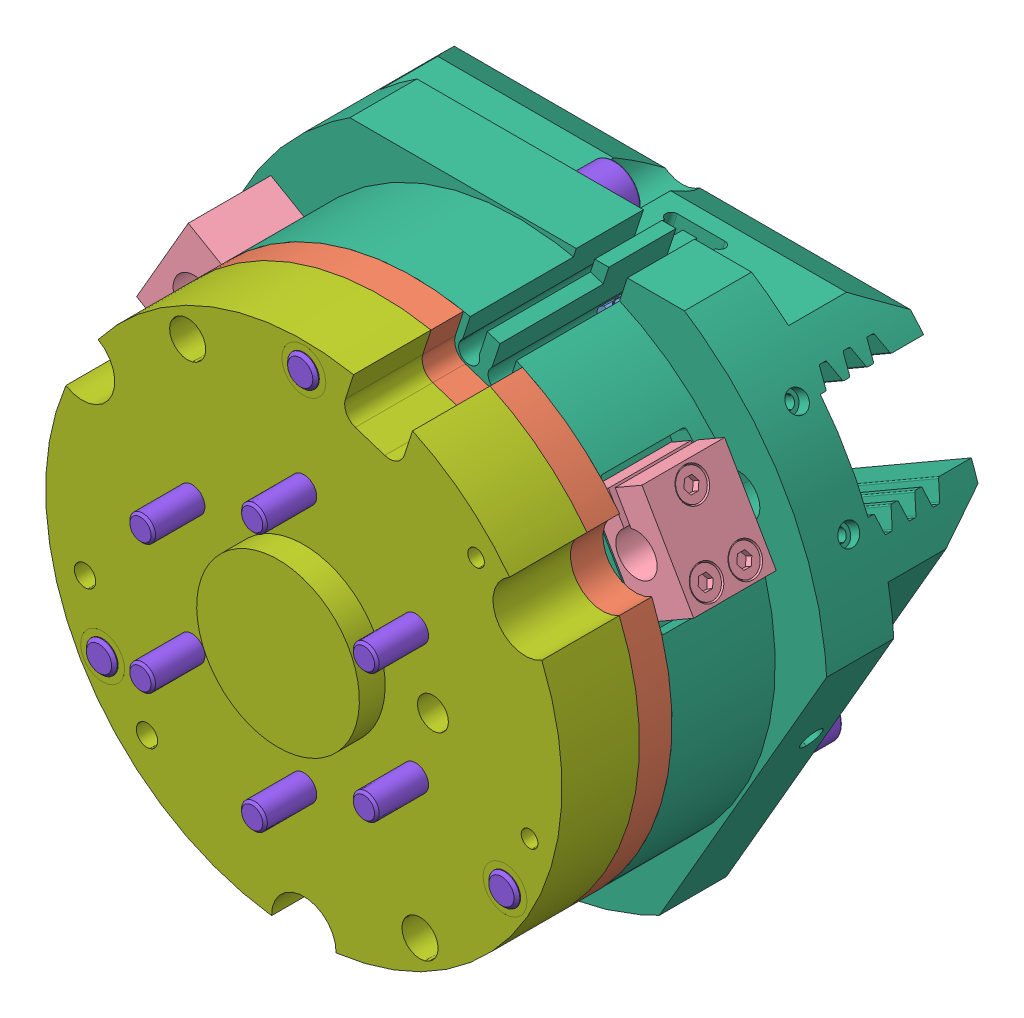
SolidWorks assembly pinza, configuration Default. Lengths in mm.
Overall size (155.63 159.06 83.8).
20 component instances, 9 part files, 17 mates.
Components (placement in the parent):
- SCHUNK_0303312_PZN_plus_100_1__00000-1: SCHUNK_0303312_PZN_plus_100_1__00000 [Default] at (-15.6229 -1.3194 144.3) x (0 -1 0) z (0 0 -1) size (159.06 155.63 58.8)
  - SCHUNK_0303312_PZN_plus_100_1__00000_3-1: SCHUNK_0303312_PZN_plus_100_1__00000_3 [Default] at (-39.3115 -15.8193 29.8) x (0.374607 -0.927184 0) z (0 0 -1) size (3.8 2.96 5)
  - SCHUNK_0303312_PZN_plus_100_1__00000_9-1: SCHUNK_0303312_PZN_plus_100_1__00000_9 [Default] at (0 0 6.3) x (0.866025 -0.5 0) z (0.5 0.866025 0) size (100 6.3 99.61)
  - SCHUNK_0303312_PZN_plus_100_1__00000_11-1: SCHUNK_0303312_PZN_plus_100_1__00000_11 [Default] at (-0.8084 39.8998 57.6) x (0.866025 -0.5 0) z (0 0 1) size (24 9 0.3)
  - SCHUNK_0303312_PZN_plus_100_1__00000_13-1: SCHUNK_0303312_PZN_plus_100_1__00000_13 [Default] at (44.5 0 6.55) x (1 0 0) z (0 -1 0) size (12 16 20)
  - SCHUNK_0303312_PZN_plus_100_1__00000_13-2: SCHUNK_0303312_PZN_plus_100_1__00000_13 [Default] at (-22.25 -38.5381 6.55) x (-0.5 -0.866025 0) z (-0.866025 0.5 0) size (12 16 20)
  - SCHUNK_0303312_PZN_plus_100_1__00000_13-3: SCHUNK_0303312_PZN_plus_100_1__00000_13 [Default] at (-22.25 38.5381 6.55) x (-0.5 0.866025 0) z (0.866025 0.5 0) size (12 16 20)
  - SCHUNK_0303312_PZN_plus_100_1__00000_17-1: SCHUNK_0303312_PZN_plus_100_1__00000_17 [Default] at (0 0 57.3) x (0.5 0.866025 0) z (0.866025 -0.5 0) size (41 1.5 41)
  - SCHUNK_0303312_PZN_plus_100_1__00000_19-1: SCHUNK_0303312_PZN_plus_100_1__00000_19 [Default] at (0 0 6.3) x (-0.866025 0.5 0) z (0.5 0.866025 0) size (119.87 52 110.5)
- IRB4600_20kg-250_LINK6_CAD_rev04.step-1: IRB4600_20kg-250_LINK6_CAD_rev04.step [Default] at (-1780.6229 -1.3194 1649.3) x (0 0 -1) z (1 0 0) size (34 63 63) (hidden)
- flangia-1: flangia [Default] at (-15.6229 -1.3194 144.3) x (0.5 -0.866025 0) z (0 0 1) size (100 99.61 20)
- socket head cap screw_iso-1: socket head cap screw_iso [ISO 4762 M6 x 55 - 24N] at (23.3477 -23.8184 99) x (0 0 1) z (-1 0 0) size (61 10 10)
- socket head cap screw_iso-2: socket head cap screw_iso [ISO 4762 M6 x 55 - 24N] at (-54.5929 -23.8194 99) x (0 0 1) z (0.5 0.866025 0) size (61 10 10)
- socket head cap screw_iso-3: socket head cap screw_iso [ISO 4762 M6 x 55 - 24N] at (-15.6235 43.6796 99) x (0 0 1) z (0.5 -0.866025 0) size (61 10 10)
- socket head cap screw_iso-4: socket head cap screw_iso [ISO 4762 M5 x 20 - 20N] at (-37.2735 -13.8194 144.3) x (0 0 1) z (-1 0 0) size (25 8.5 8.5)
- socket head cap screw_iso-5: socket head cap screw_iso [ISO 4762 M5 x 20 - 20N] at (-15.6229 -26.3194 144.3) x (0 0 1) z (-0.5 -0.866025 0) size (25 8.5 8.5)
- socket head cap screw_iso-6: socket head cap screw_iso [ISO 4762 M5 x 20 - 20N] at (6.0277 -13.8194 144.3) x (0 0 1) z (0.5 -0.866025 0) size (25 8.5 8.5)
- socket head cap screw_iso-7: socket head cap screw_iso [ISO 4762 M5 x 20 - 20N] at (6.0277 11.1806 144.3) x (0 0 1) z (1 0 0) size (25 8.5 8.5)
- socket head cap screw_iso-8: socket head cap screw_iso [ISO 4762 M5 x 20 - 20N] at (-15.6229 23.6806 144.3) x (0 0 1) z (0.5 0.866025 0) size (25 8.5 8.5)
- socket head cap screw_iso-9: socket head cap screw_iso [ISO 4762 M5 x 20 - 20N] at (-37.2735 11.1806 144.3) x (0 0 1) z (-0.5 0.866025 0) size (25 8.5 8.5)
Mates (geometry in assembly coordinates):
- Distanza3: distance = 2 mm anti-aligned: plane of chela-2/Asta_chela-1 through (2.4772 -5.3636 85) normal (-1 0 0); plane of chela-1/Asta_chela-1 through (0.4772 -5.3636 85) normal (1 0 0)
- Distanza4: distance = 2 mm anti-aligned: plane of chela-3/Asta_chela-1 through (1.9772 -6.2296 75) normal (-0.5 0.866025 0); plane of chela-1/Asta_chela-1 through (0.9772 -4.4976 85) normal (0.5 -0.866025 0)
- Distanza5: distance = 2 mm anti-aligned: plane of chela-2/Asta_chela-1 through (1.9772 -4.4976 85) normal (-0.5 -0.866025 0); plane of chela-3/Asta_chela-1 through (0.9772 -6.2296 75) normal (0.5 0.866025 0)
- Distanza6: distance = 8.5 mm aligned: plane of chela-1/Asta_chela-1 through (5.2272 1.1316 85) normal (0.5 0.866025 0); plane of chela-3/Asta_chela-1 through (0.9772 -6.2296 75) normal (0.5 0.866025 0)
- Coincidente9: coincident anti-aligned: plane of chela-2/Asta_chela-1 through (1.4772 -5.3636 85) normal (0 0 1); plane of SCHUNK_0303312_PZN_plus_100_1__00000-1/SCHUNK_0303312_PZN_plus_100_1__00000_5-1 through (52.2595 13.6788 85) normal (0 0 -1)
- Concentrico1: concentric aligned: cylinder of chela-2/Asta_chela-1 through (42.6134 18.3864 75) axis (0 0 1) radius 2.46; cylinder of SCHUNK_0303312_PZN_plus_100_1__00000-1/SCHUNK_0303312_PZN_plus_100_1__00000_5-1 through (42.6134 18.3864 101.0026) axis (0 0 1) radius 2.4585
- Concentrico2: concentric aligned: cylinder of chela-2/Asta_chela-1 through (25.2929 8.3864 75) axis (0 0 1) radius 2.46; cylinder of SCHUNK_0303312_PZN_plus_100_1__00000-1/SCHUNK_0303312_PZN_plus_100_1__00000_5-1 through (25.2929 8.3864 101.0026) axis (0 0 1) radius 2.4585
- Distanza7: distance = 15 mm anti-aligned: plane of SCHUNK_0303312_PZN_plus_100_1__00000-1/SCHUNK_0303312_PZN_plus_100_1__00000_9-1 through (-15.6229 -1.3194 143.8) normal (0 0 1); plane of IRB4600_20kg-250_LINK6_CAD_rev04.step-1 through (-15.6229 14.4306 158.8) normal (0 0 -1)
- Concentrico3: concentric aligned: circle of SCHUNK_0303312_PZN_plus_100_1__00000-1/SCHUNK_0303312_PZN_plus_100_1__00000_9-1; circle of IRB4600_20kg-250_LINK6_CAD_rev04.step-1
- SulPosto1: in place: plane of ? through (-21.3367 -2.6007 144.3) normal (0 0 1); plane of ? through (0 0 144.3) normal (0 0 1); moOrthogonalPlaneRef_w of ? through (-21.3367 -2.6007 144.3) normal (0 0 1); plane of ? through (0 0 144.3) normal (0 1 0); plane of ? through (-21.3367 -2.6007 144.3) normal (0 0 1); plane of ? through (0 0 144.3) normal (1 0 0); plane of SCHUNK_0303312_PZN_plus_100_1__00000-1/SCHUNK_0303312_PZN_plus_100_1__00000_9-1 through (-15.6229 -1.3194 144.3) normal (0 0 1); unknown of flangia-1
- Coincidente11: coincident aligned: plane of SCHUNK_0303312_PZN_plus_100_1__00000-1/SCHUNK_0303312_PZN_plus_100_1__00000_9-1; plane of flangia-1
- Coincidente12: coincident aligned: moOrthogonalPlaneRef_w of SCHUNK_0303312_PZN_plus_100_1__00000-1/SCHUNK_0303312_PZN_plus_100_1__00000_9-1 through (-15.6229 -1.3194 144.3) normal (0.866025 0.5 0); plane of flangia-1 through (-15.6229 -1.3194 144.3) normal (0.866025 0.5 0)
- Coincidente13: coincident anti-aligned: moOrthogonalPlaneRef_w of SCHUNK_0303312_PZN_plus_100_1__00000-1/SCHUNK_0303312_PZN_plus_100_1__00000_9-1 through (-15.6229 -1.3194 144.3) normal (-0.5 0.866025 0); plane of flangia-1 through (-15.6229 -1.3194 144.3) normal (0.5 -0.866025 0)
- Concentrico5: concentric aligned: cylinder of flangia-1 through (23.3477 -23.8184 159.3) axis (0 0 -1) radius 4.25; cylinder of socket head cap screw_iso-1 through (23.3477 -23.8184 67.25) axis (0 0 -1) radius 5
- Coincidente15: coincident anti-aligned: plane of SCHUNK_0303312_PZN_plus_100_1__00000-1/SCHUNK_0303312_PZN_plus_100_1__00000_19-1 through (6.3386 -83.2809 105) normal (0 0 -1); plane of socket head cap screw_iso-1 through (23.3477 -18.8184 105) normal (0 0 1)
- Concentrico6: concentric aligned: cylinder of IRB4600_20kg-250_LINK6_CAD_rev04.step-1 through (-37.2735 -13.8194 158.8) axis (0 0 -1) radius 2.5; cylinder of socket head cap screw_iso-4 through (-37.2735 -13.8194 112.55) axis (0 0 -1) radius 4.25
- Coincidente16: coincident anti-aligned: plane of flangia-1 through (-37.2735 -13.8194 149.3) normal (0 0 -1); plane of socket head cap screw_iso-4 through (-37.2735 -9.5694 149.3) normal (0 0 1)
